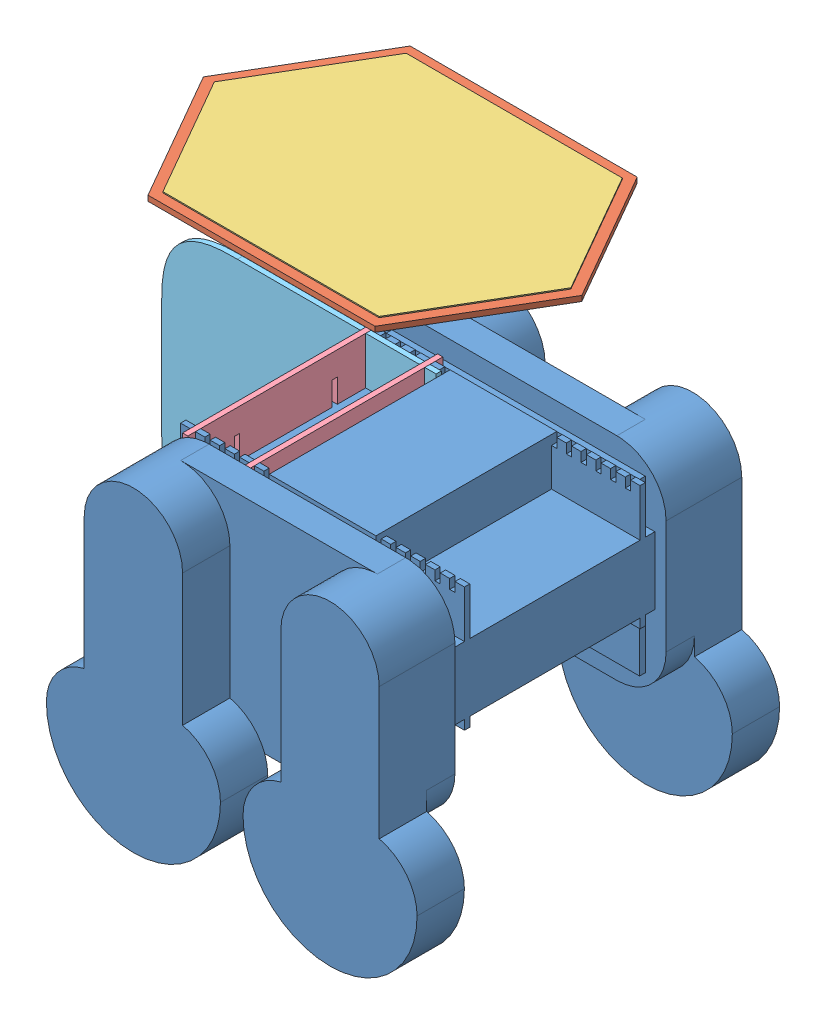
SolidWorks assembly Сборка, configuration По умолчанию. Lengths in mm.
Overall size (273.01 255.28 191.6).
6 component instances, 5 part files, 11 mates.
Components (placement in the parent):
- Механизм (как целое)-1: Механизм (как целое) [По умолчанию] at (36.0466 122.4966 69.9897) size (195.92 167 191.6)
- Верхняя плита дерево-1: Верхняя плита дерево [По умолчанию] at (96.7198 278.4246 94.2607) x (1 0 0) z (0 0.007256 0.999974) size (200 2.8 138.56)
- Верхняя плита пластик-1: Верхняя плита пластик [По умолчанию] at (96.7198 281.8245 94.236) x (1 0 0) z (0 -0.007256 -0.999974) size (188.45 20.6 128.56)
- Верхняя поперечная балка-2: Верхняя поперечная балка [По умолчанию] at (41.0466 163.0966 169.5897) x (0 0 -1) z (0 -1 0) size (103.6 2.8 25)
- Верхняя поперечная балка-3: Верхняя поперечная балка [По умолчанию] at (75.0466 163.0966 65.9897) x (0 0 1) z (0 -1 0) size (103.6 2.8 25)
- Полозья-1: Полозья [По умолчанию] at (175.3658 216.9021 72.7897) size (150.1 140.7 2.9)
Mates (geometry in assembly coordinates):
- Coincident4: coincident anti-aligned: plane of Верхняя плита дерево-1 through (71.7198 278.3982 90.6281) normal (1 0 0); plane of Верхняя плита пластик-1 through (71.7198 261.2514 98.0181) normal (-1 0 0)
- Coincident5: coincident anti-aligned: plane of Верхняя плита дерево-1 through (82.9001 278.4246 94.2607) normal (-0.809017 0.004265 0.58777); plane of Верхняя плита пластик-1 through (78.6296 261.1824 88.5078) normal (0.809017 -0.004265 -0.58777)
- Coincident6: coincident anti-aligned: plane of Верхняя плита дерево-1 through (96.7198 281.2245 94.2404) normal (0 0.999974 -0.007256); plane of Верхняя плита пластик-1 through (96.7198 281.2245 94.2404) normal (0 -0.999974 0.007256)
- Coincident7: coincident anti-aligned: plane of Механизм (как целое)-1 through (36.0466 122.4966 165.5897) normal (0 0 1); plane of Верхняя поперечная балка-2 through (43.8466 183.0966 165.5897) normal (0 0 -1)
- Coincident8: coincident anti-aligned: line of Механизм (как целое)-1 through (43.8466 183.0966 165.5897) axis (0 0 -1); line of Верхняя поперечная балка-2 through (43.8466 183.0966 159.9897) axis (0 0 1)
- Coincident9: coincident: plane of Механизм (как целое)-1 through (36.0466 188.0966 165.5897) normal (0 1 0); line of Верхняя поперечная балка-2 through (43.8466 188.0966 169.5897) axis (0 0 -1)
- Coincident10: coincident anti-aligned: plane of Механизм (как целое)-1 through (36.0466 122.4966 165.5897) normal (0 0 1); plane of Верхняя поперечная балка-3 through (72.2466 163.0966 165.5897) normal (0 0 -1)
- Coincident11: coincident anti-aligned: line of Механизм (как целое)-1 through (72.2466 183.0966 162.7897) axis (0 0 1); line of Верхняя поперечная балка-3 through (72.2466 183.0966 165.5897) axis (0 0 -1)
- Coincident12: coincident aligned: line of Механизм (как целое)-1 through (72.2466 188.0966 162.7897) axis (0 0 1); line of Верхняя поперечная балка-3 through (72.2466 188.0966 65.9897) axis (0 0 1)
- Coincident14: coincident aligned: line of Механизм (как целое)-1 through (80.0466 188.0966 72.7897) axis (-1 0 0); line of Полозья-1 through (81.0466 188.0966 72.7897) axis (-1 0 0)
- Coincident15: coincident aligned: line of Механизм (как целое)-1 through (72.2466 183.0966 72.7897) axis (0 1 0); line of Полозья-1 through (72.2466 183.0966 72.7897) axis (0 1 0)
